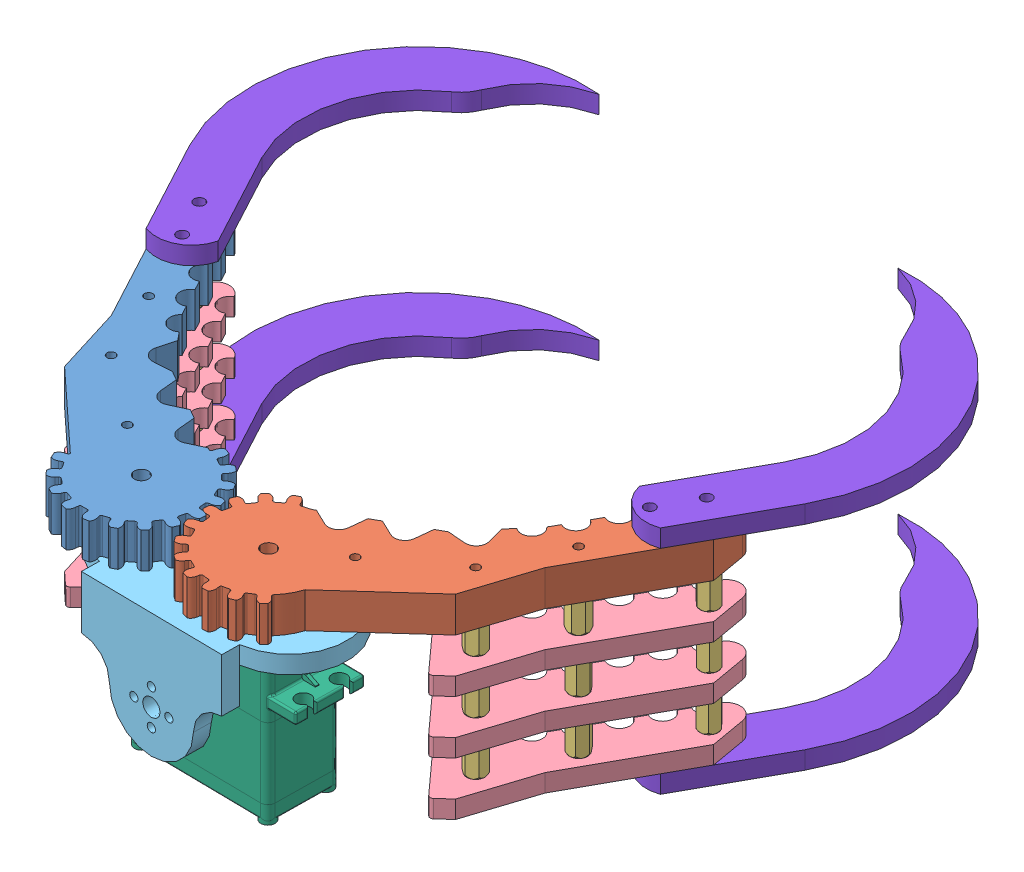
SolidWorks assembly Gripper_Assembly, configuration Default. Lengths in mm.
Overall size (219.93 65 185.83).
33 component instances, 8 part files, 77 mates.
Components (placement in the parent):
- Gripper_Finger_Driven-1: Gripper_Finger_Driven [Default] at (-7.6318 0 118.5221) x (0.679527 0 -0.733651) z (0.733651 0 0.679527) size (41.12 10 113.36)
- Gripper_Finger_Driver-1: Gripper_Finger_Driver [Default] at (-87.7599 0 -9.7475) x (0.6706 0 0.741819) z (-0.741819 0 0.6706) size (41.13 10 113.29)
- Hex Spacer FF M3 L10mm-1: Hex Spacer FF M3 L10mm [Default] at (-96.5447 -10 70.5822) x (0.849802 0 -0.527102) z (0 -1 0) size (5.01 5.78 10.01)
- Hex Spacer FF M3 L10mm-2: Hex Spacer FF M3 L10mm [Default] at (-85.6763 -10 55.1873) x (0.884943 0 0.465699) z (0 -1 0) size (5.01 5.78 10.01)
- Hex Spacer FF M3 L10mm-4: Hex Spacer FF M3 L10mm [Default] at (-34.0651 -10 54.1646) x (-0.176056 0 0.98438) z (0 -1 0) size (5.01 5.78 10.01)
- Gripper_Finger-1: Gripper_Finger [Default] at (-22.9204 -15 123.245) x (0.679527 0 -0.733651) z (0.733651 0 0.679527) size (35.99 5 61.76)
- Hex Spacer FF M3 L10mm-5: Hex Spacer FF M3 L10mm [Default] at (-80.214 -25 13.6083) x (0.441533 0 0.897245) z (0 -1 0) size (5.01 5.78 10.01)
- Hex Spacer FF M3 L10mm-6: Hex Spacer FF M3 L10mm [Default] at (-34.2929 -25 37.1465) x (-0.399611 0 0.916685) z (0 -1 0) size (5.01 5.78 10.01)
- Hex Spacer FF M3 L10mm-7: Hex Spacer FF M3 L10mm [Default] at (-12.9482 -25 65.134) x (-0.704122 0 0.710079) z (0 -1 0) size (5.01 5.78 10.01)
- Gripper_Finger-2: Gripper_Finger [Default] at (-22.9204 -30 123.245) x (0.679527 0 -0.733651) z (0.733651 0 0.679527) size (35.99 5 61.76)
- Gripper_Finger-3: Gripper_Finger [Default] at (-22.9204 -45 123.245) x (0.679527 0 -0.733651) z (0.733651 0 0.679527) size (35.99 5 61.76)
- Hex Spacer FF M3 L10mm-9: Hex Spacer FF M3 L10mm [Default] at (-101.2882 -40 59.4759) x (0.968389 0 -0.249444) z (0 -1 0) size (5.01 5.78 10.01)
- Hex Spacer FF M3 L10mm-10: Hex Spacer FF M3 L10mm [Default] at (-31.2734 -40 38.6165) x (-0.475098 0 0.879933) z (0 -1 0) size (5.01 5.78 10.01)
- Hex Spacer FF M3 L10mm-11: Hex Spacer FF M3 L10mm [Default] at (-14.853 -40 63.3641) x (-0.6565 0 0.754326) z (0 -1 0) size (5.01 5.78 10.01)
- Gripper_Finger-4: Gripper_Finger [Default] at (43.4255 -10 123.4296) x (-0.6706 0 -0.741819) z (-0.741819 0 0.6706) size (35.99 5 61.76)
- Hex Spacer FF M3 L10mm-12: Hex Spacer FF M3 L10mm [Default] at (123.1318 -10 58.203) x (-0.979615 0 -0.200883) z (0 -1 0) size (5.01 5.78 10.01)
- Hex Spacer FF M3 L10mm-13: Hex Spacer FF M3 L10mm [Default] at (101.9345 -10 95.6454) x (-0.999098 0 -0.042467) z (0 -1 0) size (5.01 5.78 10.01)
- Hex Spacer FF M3 L10mm-14: Hex Spacer FF M3 L10mm [Default] at (99.2944 -10 102.9837) x (-0.697865 0 -0.716229) z (0 -1 0) size (5.01 5.78 10.01)
- Hex Spacer FF M3 L10mm-15: Hex Spacer FF M3 L10mm [Default] at (122.8316 -25 59.5484) x (-0.972112 0 -0.234518) z (0 -1 0) size (5.01 5.78 10.01)
- Hex Spacer FF M3 L10mm-16: Hex Spacer FF M3 L10mm [Default] at (80.7268 -25 129.2771) x (-0.468764 0 -0.883323) z (0 -1 0) size (5.01 5.78 10.01)
- Hex Spacer FF M3 L10mm-17: Hex Spacer FF M3 L10mm [Default] at (107.9577 -25 90.5183) x (-0.914481 0 -0.40463) z (0 -1 0) size (5.01 5.78 10.01)
- Gripper_Finger-5: Gripper_Finger [Default] at (43.4255 -25 123.4296) x (-0.6706 0 -0.741819) z (-0.741819 0 0.6706) size (35.99 5 61.76)
- Hex Spacer FF M3 L10mm-18: Hex Spacer FF M3 L10mm [Default] at (122.1386 -40 62.0593) x (-0.954787 0 -0.297291) z (0 -1 0) size (5.01 5.78 10.01)
- Hex Spacer FF M3 L10mm-19: Hex Spacer FF M3 L10mm [Default] at (107.0482 -40 92.4348) x (-0.891744 0 -0.452541) z (0 -1 0) size (5.01 5.78 10.01)
- Hex Spacer FF M3 L10mm-20: Hex Spacer FF M3 L10mm [Default] at (80.653 -40.003 129.3161) x (-0.466918 0 -0.884301) z (0 -1 0) size (5.01 5.78 10.01)
- Gripper_Finger-7: Gripper_Finger [Default] at (43.4255 -40 123.4296) x (-0.6706 0 -0.741819) z (-0.741819 0 0.6706) size (35.99 5 61.76)
- Gripper_Connector-1: Gripper_Connector [Default] at (-3.905 -6.4 134.0757) x (0.999903 0 0.013955) z (-0.013955 0 0.999903) size (68 35 37)
- Servo 20kg-1: Servo 20kg [Default] at (18.2462 -48.05 118.3833) x (0.999903 0 0.013955) z (-0.013955 0 0.999903) size (55.1 45.65 20.12)
- microservoArm-1: microservoArm [A3] at (28.1952 0 118.5221) x (0.788043 0 -0.61562) z (-0.61562 0 -0.788043) size (20.7 3.9 7)
- Finger_Extension-1: Finger_Extension [Default] at (-55.5353 10 59.1225) x (-0.472448 0 -0.881359) z (0.881359 0 -0.472448) size (81.26 5 73.02)
- Finger_Extension-2: Finger_Extension [Default] at (76.8082 -45 59.7167) x (0.483077 0 -0.875578) z (-0.875578 0 -0.483077) size (81.26 5 73.02)
- Finger_Extension-3: Finger_Extension [Default] at (-55.5353 -50 59.1225) x (-0.472448 0 -0.881359) z (0.881359 0 -0.472448) size (81.26 5 73.02)
- Finger_Extension-5: Finger_Extension [Default] at (76.8082 15 59.7167) x (0.483077 0 -0.875578) z (-0.875578 0 -0.483077) size (81.26 5 73.02)
Mates (geometry in assembly coordinates):
- Coincident1: coincident anti-aligned: plane of Gripper_Finger_Driven-1 through (-7.6318 0 118.5221) normal (0 -1 0)
- Coincident2: coincident aligned: plane of Gripper_Finger_Driven-1 through (-7.6318 0 118.5221) normal (0 -1 0); plane of Gripper_Finger_Driver-1 through (-87.7599 0 -9.7475) normal (0 -1 0)
- Coincident3: coincident: point of Gripper_Finger_Driver-1
- Coincident4: coincident: unknown of Gripper_Finger_Driven-1
- GearMate5: gear = 1 : 1 mm: cylinder of Gripper_Finger_Driven-1 through (-7.6318 0 118.5221) axis (0 1 0) radius 2; cylinder of Gripper_Finger_Driver-1 through (28.1952 0 118.5221) axis (0 1 0) radius 2
- Tangent3: tangent anti-aligned: cylinder of Gripper_Finger_Driven-1 through (-62.5526 0 49.4981) axis (0 1 0) radius 1.2; face of Hex Spacer FF M3 L10mm-1
- Coincident5: coincident anti-aligned: plane of Gripper_Finger_Driven-1 through (-7.6318 0 118.5221) normal (0 -1 0); plane of Hex Spacer FF M3 L10mm-1 through (-66.0638 0 48.6752) normal (0 1 0)
- Coincident7: coincident anti-aligned: plane of Gripper_Finger_Driven-1 through (-7.6318 0 118.5221) normal (0 -1 0); plane of Hex Spacer FF M3 L10mm-2 through (-51.3477 0 70.3711) normal (0 1 0)
- Tangent5: tangent anti-aligned: cylinder of Gripper_Finger_Driven-1 through (-50.2786 0 73.8152) axis (0 1 0) radius 1.2; edge_curve of Hex Spacer FF M3 L10mm-2
- Coincident9: coincident anti-aligned: plane of Gripper_Finger_Driven-1 through (-7.6318 0 118.5221) normal (0 -1 0); plane of Hex Spacer FF M3 L10mm-4 through (-38.1483 0 91.4786) normal (0 1 0)
- Tangent6: tangent anti-aligned: cylinder of Gripper_Finger_Driven-1 through (-41.1074 0 93.5398) axis (0 1 0) radius 1.2; edge_curve of Hex Spacer FF M3 L10mm-4
- Concentric1: concentric aligned: cylinder of Gripper_Finger_Driven-1 through (-62.5526 0 49.4981) axis (0 1 0) radius 1.2; cylinder of Gripper_Finger-1 through (-62.5526 -15 49.4981) axis (0 1 0) radius 1.2
- Coincident13: coincident anti-aligned: plane of Hex Spacer FF M3 L10mm-1 through (-66.0638 -10 48.6752) normal (0 -1 0); plane of Gripper_Finger-1 through (-61.5998 -10 43.816) normal (0 1 0)
- Parallel5: parallel aligned: plane of Gripper_Finger_Driven-1 through (-17.0476 10 128.6879) normal (-0.679527 0 0.733651); plane of Gripper_Finger-1 through (-22.9204 -10 123.245) normal (-0.679527 0 0.733651)
- Coincident15: coincident anti-aligned: plane of Gripper_Finger-1 through (-61.5998 -15 43.816) normal (0 -1 0); plane of Hex Spacer FF M3 L10mm-5 through (-61.3906 -15 46.0842) normal (0 1 0)
- Coincident16: coincident anti-aligned: plane of Gripper_Finger-1 through (-61.5998 -15 43.816) normal (0 -1 0); plane of Hex Spacer FF M3 L10mm-6 through (-46.9208 -15 72.4953) normal (0 1 0)
- Coincident17: coincident anti-aligned: plane of Gripper_Finger-1 through (-61.5998 -15 43.816) normal (0 -1 0); plane of Hex Spacer FF M3 L10mm-7 through (-37.5068 -15 93.522) normal (0 1 0)
- Tangent10: tangent anti-aligned: cylinder of Gripper_Finger-1 through (-62.5526 -15 49.4981) axis (0 1 0) radius 1.2; edge_curve of Hex Spacer FF M3 L10mm-5
- Tangent11: tangent anti-aligned: cylinder of Gripper_Finger-1 through (-50.2773 -15 73.8139) axis (0 1 0) radius 1.2; edge_curve of Hex Spacer FF M3 L10mm-6
- Tangent12: tangent anti-aligned: cylinder of Gripper_Finger-1 through (-41.113 -15 93.5372) axis (0 1 0) radius 1.2; edge_curve of Hex Spacer FF M3 L10mm-7
- Concentric2: concentric aligned: cylinder of Gripper_Finger_Driven-1 through (-62.5526 0 49.4981) axis (0 1 0) radius 1.2; cylinder of Gripper_Finger-2 through (-62.5526 -30 49.4981) axis (0 1 0) radius 1.2
- Coincident23: coincident anti-aligned: plane of Hex Spacer FF M3 L10mm-5 through (-61.3906 -25 46.0842) normal (0 -1 0); plane of Gripper_Finger-2 through (-61.5998 -25 43.816) normal (0 1 0)
- Parallel10: parallel aligned: plane of Gripper_Finger_Driven-1 through (-17.0476 10 128.6879) normal (-0.679527 0 0.733651); plane of Gripper_Finger-2 through (-22.9204 -25 123.245) normal (-0.679527 0 0.733651)
- Coincident25: coincident anti-aligned: plane of Gripper_Finger-2 through (-61.5998 -30 43.816) normal (0 -1 0); plane of Hex Spacer FF M3 L10mm-9 through (-65.6581 -30 47.6648) normal (0 1 0)
- Coincident26: coincident anti-aligned: plane of Gripper_Finger-2 through (-61.5998 -30 43.816) normal (0 -1 0); plane of Hex Spacer FF M3 L10mm-10 through (-46.822 -30 72.7815) normal (0 1 0)
- Coincident27: coincident anti-aligned: plane of Gripper_Finger-2 through (-61.5998 -30 43.816) normal (0 -1 0); plane of Hex Spacer FF M3 L10mm-11 through (-37.5154 -30 93.2877) normal (0 1 0)
- Tangent14: tangent anti-aligned: cylinder of Gripper_Finger-2 through (-62.5526 -30 49.4981) axis (0 1 0) radius 1.2; edge_curve of Hex Spacer FF M3 L10mm-9
- Tangent15: tangent anti-aligned: cylinder of Gripper_Finger-2 through (-50.2773 -30 73.8139) axis (0 1 0) radius 1.2; edge_curve of Hex Spacer FF M3 L10mm-10
- Tangent16: tangent anti-aligned: cylinder of Gripper_Finger-2 through (-41.113 -30 93.5372) axis (0 1 0) radius 1.2; edge_curve of Hex Spacer FF M3 L10mm-11
- Concentric3: concentric aligned: cylinder of Gripper_Finger_Driven-1 through (-62.5526 0 49.4981) axis (0 1 0) radius 1.2; cylinder of Gripper_Finger-3 through (-62.5526 -45 49.4981) axis (0 1 0) radius 1.2
- Coincident31: coincident anti-aligned: plane of Gripper_Finger-3 through (-61.5998 -40 43.816) normal (0 1 0); plane of Hex Spacer FF M3 L10mm-9 through (-65.6581 -40 47.6648) normal (0 -1 0)
- Parallel14: parallel aligned: plane of Gripper_Finger_Driven-1 through (-17.0476 10 128.6879) normal (-0.679527 0 0.733651); plane of Gripper_Finger-3 through (-22.9204 -40 123.245) normal (-0.679527 0 0.733651)
- Coincident33: coincident anti-aligned: plane of Gripper_Finger_Driver-1 through (-87.7599 0 -9.7475) normal (0 -1 0); plane of Hex Spacer FF M3 L10mm-12 through (85.9329 0 53.178) normal (0 1 0)
- Tangent17: tangent anti-aligned: cylinder of Gripper_Finger_Driver-1 through (83.9471 0 50.1677) axis (0 1 0) radius 1.2; edge_curve of Hex Spacer FF M3 L10mm-12
- Coincident35: coincident anti-aligned: plane of Gripper_Finger-4 through (83.0631 -10 44.4744) normal (0 1 0); plane of Hex Spacer FF M3 L10mm-12 through (85.9329 -10 53.178) normal (0 -1 0)
- Tangent19: tangent anti-aligned: cylinder of Gripper_Finger-4 through (83.9471 -10 50.1677) axis (0 -1 0) radius 1.2; edge_curve of Hex Spacer FF M3 L10mm-12
- Coincident36: coincident anti-aligned: plane of Gripper_Finger_Driver-1 through (-87.7599 0 -9.7475) normal (0 -1 0); plane of Hex Spacer FF M3 L10mm-14 through (71.3329 0 77.9405) normal (0 1 0)
- Coincident37: coincident anti-aligned: plane of Gripper_Finger_Driver-1 through (-87.7599 0 -9.7475) normal (0 -1 0); plane of Hex Spacer FF M3 L10mm-13 through (64.41 0 96.6027) normal (0 1 0)
- Tangent20: tangent anti-aligned: cylinder of Gripper_Finger_Driver-1 through (71.3798 0 74.3345) axis (0 1 0) radius 1.2; edge_curve of Hex Spacer FF M3 L10mm-14
- Tangent21: tangent anti-aligned: cylinder of Gripper_Finger_Driver-1 through (61.9706 0 93.9467) axis (0 1 0) radius 1.2; edge_curve of Hex Spacer FF M3 L10mm-13
- Parallel16: parallel aligned: plane of Gripper_Finger_Driver-1 through (37.4873 10 128.8011) normal (0.6706 0 0.741819); plane of Gripper_Finger-4 through (43.4255 -15 123.4296) normal (0.6706 0 0.741819)
- Coincident39: coincident anti-aligned: plane of Gripper_Finger-4 through (83.0631 -15 44.4744) normal (0 -1 0); plane of Hex Spacer FF M3 L10mm-16 through (60.9191 -15 97.3919) normal (0 1 0)
- Coincident40: coincident anti-aligned: plane of Gripper_Finger-4 through (83.0631 -15 44.4744) normal (0 -1 0); plane of Hex Spacer FF M3 L10mm-17 through (72.6786 -15 77.6968) normal (0 1 0)
- Coincident41: coincident anti-aligned: plane of Gripper_Finger-4 through (83.0631 -15 44.4744) normal (0 -1 0); plane of Hex Spacer FF M3 L10mm-15 through (85.828 -15 53.2446) normal (0 1 0)
- Tangent22: tangent anti-aligned: cylinder of Gripper_Finger-4 through (83.9471 -10 50.1677) axis (0 -1 0) radius 1.2; edge_curve of Hex Spacer FF M3 L10mm-15
- Tangent24: tangent anti-aligned: cylinder of Gripper_Finger-4 through (71.3785 -10 74.3331) axis (0 -1 0) radius 1.2; edge_curve of Hex Spacer FF M3 L10mm-17
- Tangent25: tangent anti-aligned: cylinder of Gripper_Finger-4 through (61.9762 -10 93.9441) axis (0 -1 0) radius 1.2; edge_curve of Hex Spacer FF M3 L10mm-16
- Concentric4: concentric anti-aligned: cylinder of Gripper_Finger_Driver-1 through (83.9471 0 50.1677) axis (0 1 0) radius 1.2; cylinder of Gripper_Finger-5 through (83.9471 -25 50.1677) axis (0 -1 0) radius 1.2
- Coincident42: coincident anti-aligned: plane of Hex Spacer FF M3 L10mm-15 through (85.828 -25 53.2446) normal (0 -1 0); plane of Gripper_Finger-5 through (83.0631 -25 44.4744) normal (0 1 0)
- Parallel18: parallel aligned: plane of Gripper_Finger_Driver-1 through (37.4873 10 128.8011) normal (0.6706 0 0.741819); plane of Gripper_Finger-5 through (43.4255 -30 123.4296) normal (0.6706 0 0.741819)
- Coincident45: coincident anti-aligned: plane of Gripper_Finger-5 through (83.0631 -30 44.4744) normal (0 -1 0); plane of Hex Spacer FF M3 L10mm-18 through (85.6238 -30 53.3605) normal (0 1 0)
- Tangent26: tangent anti-aligned: cylinder of Gripper_Finger-5 through (83.9471 -25 50.1677) axis (0 -1 0) radius 1.2; edge_curve of Hex Spacer FF M3 L10mm-18
- Coincident46: coincident anti-aligned: plane of Gripper_Finger-5 through (83.0631 -30 44.4744) normal (0 -1 0); plane of Hex Spacer FF M3 L10mm-19 through (72.4985 -30 77.761) normal (0 1 0)
- Tangent27: tangent anti-aligned: cylinder of Gripper_Finger-5 through (71.3785 -25 74.3331) axis (0 -1 0) radius 1.2; edge_curve of Hex Spacer FF M3 L10mm-19
- Tangent28: tangent anti-aligned: cylinder of Gripper_Finger-5 through (61.9762 -25 93.9441) axis (0 -1 0) radius 1.2; edge_curve of Hex Spacer FF M3 L10mm-20
- Concentric5: concentric anti-aligned: cylinder of Gripper_Finger_Driver-1 through (83.9471 0 50.1677) axis (0 1 0) radius 1.2; cylinder of Gripper_Finger-7 through (83.9471 -40 50.1677) axis (0 -1 0) radius 1.2
- Coincident47: coincident anti-aligned: plane of Hex Spacer FF M3 L10mm-18 through (85.6238 -40 53.3605) normal (0 -1 0); plane of Gripper_Finger-7 through (83.0631 -40 44.4744) normal (0 1 0)
- Parallel19: parallel aligned: plane of Gripper_Finger_Driver-1 through (37.4873 10 128.8011) normal (0.6706 0 0.741819); plane of Gripper_Finger-7 through (43.4255 -45 123.4296) normal (0.6706 0 0.741819)
- Concentric6: concentric aligned: cylinder of Gripper_Finger_Driver-1 through (28.1952 0 118.5221) axis (0 1 0) radius 2; cylinder of Gripper_Connector-1 through (28.1952 -36.4 118.5221) axis (0 1 0) radius 4.955
- Concentric13: concentric anti-aligned: cylinder of Gripper_Connector-1 through (28.1952 -36.4 118.5221) axis (0 1 0) radius 4.955; cylinder of Servo 20kg-1 through (28.1952 -2.4 118.5221) axis (0 -1 0) radius 1
- Coincident48: coincident anti-aligned: plane of Gripper_Connector-1 through (-3.4584 -6.4 102.0788) normal (0 -1 0); plane of Servo 20kg-1 through (28.1952 -6.4 118.5221) normal (0 1 0)
- Tangent33: tangent aligned: cylinder of Gripper_Finger_Driven-1 through (-7.6318 0 118.5221) axis (0 1 0) radius 2; cylinder of Gripper_Connector-1 through (-7.6313 -36.4 118.0221) axis (0 1 0) radius 2.5
- Parallel27: parallel anti-aligned: plane of Gripper_Connector-1 through (-3.905 -6.4 134.0757) normal (0.013955 0 -0.999903); plane of Servo 20kg-1 through (38.154 -7.55 128.7121) normal (-0.013955 0 0.999903)
- Concentric18: concentric anti-aligned: cylinder of Servo 20kg-1 through (28.1952 -2.4 118.5221) axis (0 -1 0) radius 1; cylinder of microservoArm-1 through (28.1952 -3.9 118.5221) axis (0 1 0) radius 2.45
- Coincident50: coincident anti-aligned: plane of Gripper_Finger_Driver-1 through (-87.7599 0 -9.7475) normal (0 -1 0); plane of microservoArm-1 through (16.217 0 127.8795) normal (0 1 0)
- Coincident52: coincident anti-aligned: plane of Gripper_Connector-1 through (-3.4584 -1.4 102.0788) normal (0 1 0); plane of microservoArm-1 through (16.217 -1.4 127.8795) normal (0 -1 0)
- Parallel28: parallel aligned: plane of Gripper_Finger_Driver-1 through (37.4873 10 128.8011) normal (0.6706 0 0.741819); plane of microservoArm-1 through (31.4896 -3.9 119.704) normal (0.6706 0 0.741819)
- Coincident53: coincident aligned: plane of Gripper_Finger_Driven-1 through (-26.7193 10 128.7539) normal (-0.881359 0 0.472448); plane of Finger_Extension-1 through (-62.1455 15 62.6659) normal (-0.881359 0 0.472448)
- Coincident54: coincident anti-aligned: plane of Gripper_Finger_Driven-1 through (-7.6318 10 118.5221) normal (0 1 0); plane of Finger_Extension-1 through (-55.5353 10 59.1225) normal (0 -1 0)
- Coincident55: coincident anti-aligned: plane of Gripper_Finger-3 through (-61.5998 -45 43.816) normal (0 -1 0); plane of Finger_Extension-3 through (-55.5353 -45 59.1225) normal (0 1 0)
- Coincident56: coincident aligned: plane of Gripper_Finger-3 through (-50.8419 -40 83.7529) normal (-0.881359 0 0.472448); plane of Finger_Extension-3 through (-62.1455 -45 62.6659) normal (-0.881359 0 0.472448)
- Coincident57: coincident anti-aligned: plane of Gripper_Finger_Driver-1 through (-87.7599 10 -9.7475) normal (0 1 0); plane of Finger_Extension-5 through (76.8082 10 59.7167) normal (0 -1 0)
- Coincident58: coincident aligned: plane of Gripper_Finger_Driver-1 through (74.3522 10 79.6936) normal (0.875578 0 0.483077); plane of Finger_Extension-5 through (83.3751 10 63.3397) normal (0.875578 0 0.483077)
- Coincident60: coincident anti-aligned: plane of Gripper_Finger-7 through (83.0631 -45 44.4744) normal (0 -1 0); plane of Finger_Extension-2 through (76.8082 -45 59.7167) normal (0 1 0)
- Coincident61: coincident aligned: plane of Gripper_Finger-7 through (71.8228 -45 84.2783) normal (0.875578 0 0.483077); plane of Finger_Extension-2 through (83.3751 -50 63.3397) normal (0.875578 0 0.483077)
- Concentric21: concentric aligned: cylinder of Finger_Extension-2 through (82.5085 -50 49.3848) axis (0 1 0) radius 1.5; cylinder of Finger_Extension-5 through (82.5085 10 49.3848) axis (0 1 0) radius 1.5
- Concentric22: concentric aligned: cylinder of Finger_Extension-1 through (-61.1102 15 48.7225) axis (0 -1 0) radius 1.5; cylinder of Finger_Extension-3 through (-61.1102 -45 48.7225) axis (0 -1 0) radius 1.5
